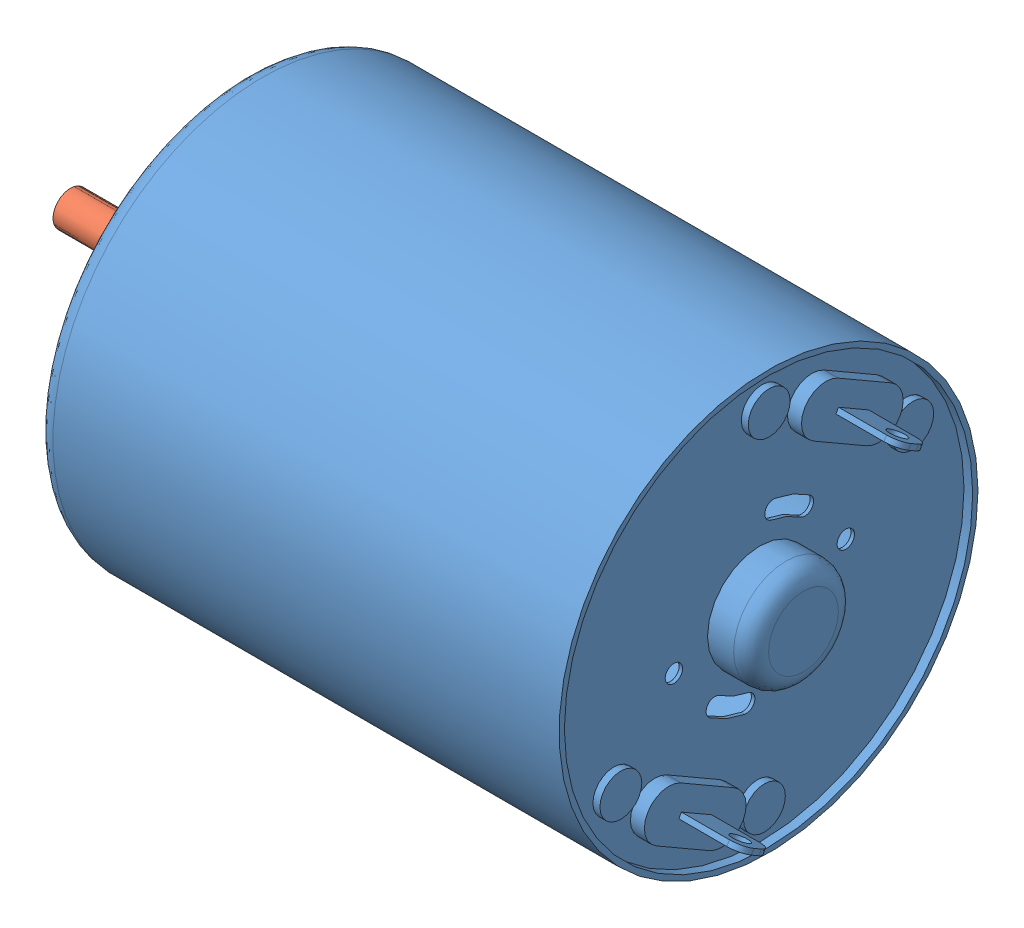
SolidWorks assembly TS-32GZ370-5300, DC MOTOR, configuration Default. Lengths in mm.
Overall size (43.8 24 24).
2 component instances, 2 part files, 3 mates.
Components (placement in the parent):
- TS-32GZ370-5300, DC MOTOR BODY-1: TS-32GZ370-5300, DC MOTOR BODY [Default] at origin size (33.8 24 24)
- TS-32GZ370-5300, DC MOTOR SHAFT-1: TS-32GZ370-5300, DC MOTOR SHAFT [Default] at (-20 0 0) x (1 0 0) z (0 0.450234 0.89291) size (40 2 2)
Mates (geometry in assembly coordinates):
- Coincident1: coordinate: point of TS-32GZ370-5300, DC MOTOR BODY-1; point of assembly
- Concentric1: concentric aligned: cylinder of TS-32GZ370-5300, DC MOTOR BODY-1 through (3.801 0 0) axis (-1 0 0) radius 1; cylinder of TS-32GZ370-5300, DC MOTOR SHAFT-1 through (0 0 0) axis (-1 0 0) radius 1
- Distance1: distance = 10 mm aligned: plane of TS-32GZ370-5300, DC MOTOR BODY-1 through (-30 0 0) normal (-1 0 0); plane of TS-32GZ370-5300, DC MOTOR SHAFT-1 through (-40 0 0) normal (-1 0 0)
